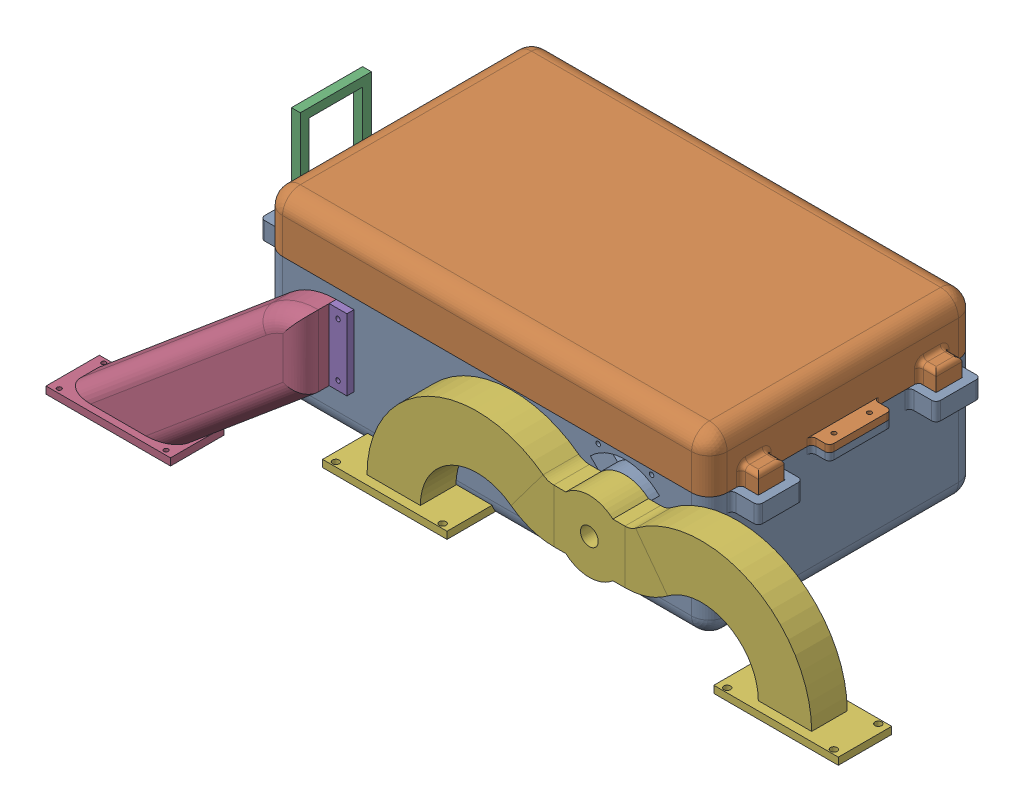
SolidWorks assembly Body, configuration Default. Lengths in mm.
Overall size (446.74 139.78 175.01).
5 component instances, 5 part files, 10 mates.
Components (placement in the parent):
- Bottom-1: Bottom [Default] at (38.0849 27.3995 96.9723) size (280 70 150)
- Top-1: Top [Default] at (38.0849 127.3995 96.9723) x (-1 0 0) z (0 0 1) size (269.75 40 150)
- Camera_Mount-1: Camera_Mount [Default] at (-106.9151 77.3995 96.9723) x (0 0 -1) z (1 0 0) size (60 55 40)
- Long Single Arm-1: Long Single Arm [Default] at (-36.7036 71.6233 175.9723) x (0 0 -1) z (1 0 0) size (30 104.87 149.45)
- Double_Mount-1: Double_Mount [Default] at (115.5849 67.3995 171.9723) size (290 65.87 30.03)
Mates (geometry in assembly coordinates):
- LimitDistance1: limit distance = 0 mm aligned: plane of Top-1 through (38.0849 87.3995 96.9723) normal (0 -1 0); plane of Bottom-1 through (38.0849 87.3995 96.9723) normal (0 -1 0)
- Coincident6: coincident aligned: plane of Bottom-1 through (-86.9151 97.3995 171.9723) normal (0 0 1); plane of Top-1 through (163.0849 97.3995 171.9723) normal (0 0 1)
- Coincident7: coincident aligned: plane of Bottom-1 through (-86.9151 97.3995 171.9723) normal (-1 0 0); plane of Top-1 through (-86.9151 97.3995 21.9723) normal (-1 0 0)
- Coincident8: coincident anti-aligned: circle of Bottom-1; cylinder of Camera_Mount-1 through (-90.9151 77.3995 121.9723) axis (1 0 0) radius 1.25
- Concentric1: concentric anti-aligned: cylinder of Bottom-1 through (-50.9151 77.3995 71.9723) axis (-1 0 0) radius 1.25; cylinder of Camera_Mount-1 through (-90.9151 77.3995 71.9723) axis (1 0 0) radius 1.25
- Coincident10: coincident anti-aligned: plane of Bottom-1 through (-86.9151 97.3995 171.9723) normal (-1 0 0); plane of Camera_Mount-1 through (-86.9151 77.3995 96.9723) normal (1 0 0)
- Coincident11: coincident aligned: circle of Bottom-1; circle of Long Single Arm-1
- Concentric2: concentric anti-aligned: cylinder of Bottom-1 through (-41.7036 56.6233 171.9723) axis (0 0 -1) radius 1.25; cylinder of Long Single Arm-1 through (-41.7036 56.6233 171.9723) axis (0 0 1) radius 1.25
- Coincident12: coincident anti-aligned: circle of Bottom-1; circle of Double_Mount-1
- Concentric3: concentric anti-aligned: cylinder of Bottom-1 through (90.5849 67.3995 171.9723) axis (0 0 -1) radius 10; cylinder of Double_Mount-1 through (90.5849 67.3995 171.9723) axis (0 0 1) radius 10
